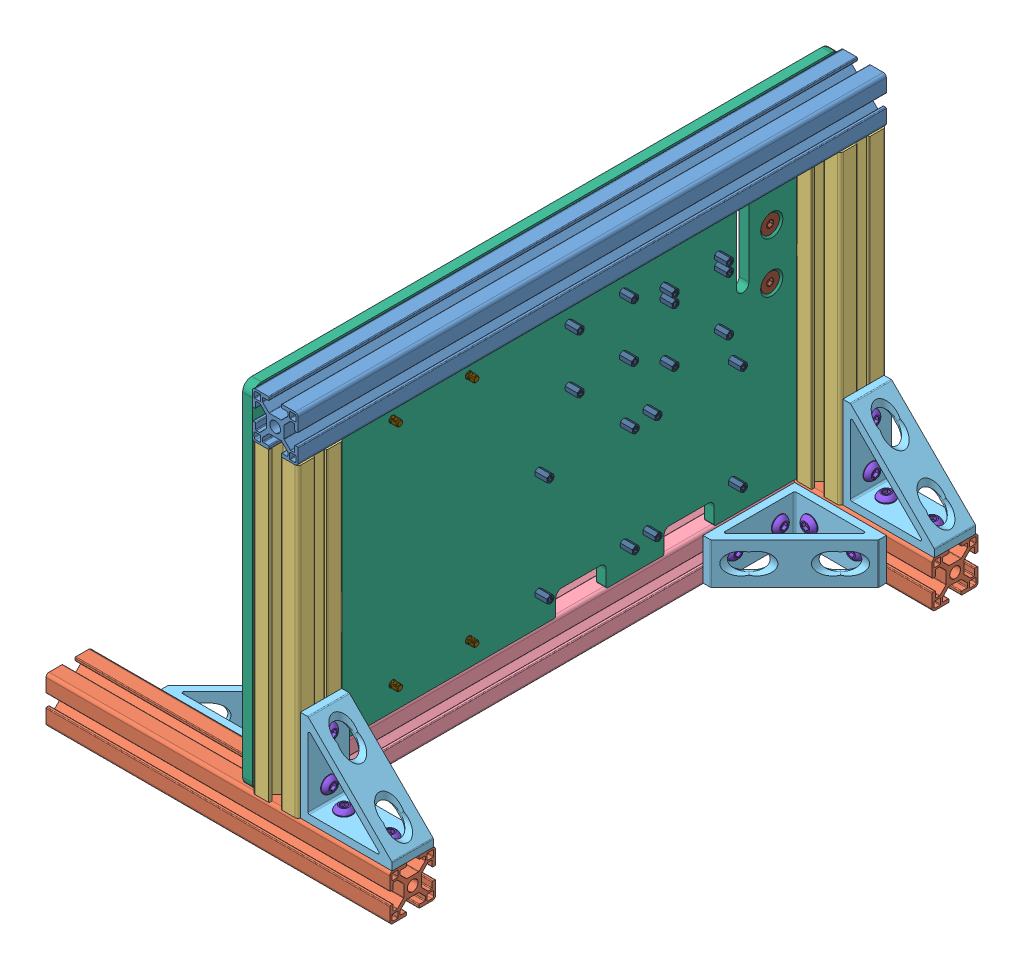
SolidWorks assembly 001 - Machine Frame, configuration Default. Lengths in mm.
Overall size (225 260 385).
71 component instances, 11 part files, 65 mates.
Components (placement in the parent):
- SP - 3030x295mm Extrusion - Phidgets TSL4002_0-1: SP - 3030x295mm Extrusion - Phidgets TSL4002_0 [5537T784] at origin size (30 30 385)
- SP - 3030x225mm Extrusion - Phidgets TSL4002_0-1: SP - 3030x225mm Extrusion - Phidgets TSL4002_0 [5537T784] at (-37.5001 -229.9999 -177.5001) x (0 0 -1) z (1 0 0) size (30 30 225)
- SP - 3030x225mm Extrusion - Phidgets TSL4002_0-2: SP - 3030x225mm Extrusion - Phidgets TSL4002_0 [5537T784] at (-37.5001 -229.9999 177.4998) x (0 0 1) z (-1 0 0) size (30 30 225)
- SP - 3030x200mm Extrusion - Phidgets TSL4002_0-1: SP - 3030x200mm Extrusion - Phidgets TSL4002_0 [5537T784] at (0 -114.9999 177.5001) x (1 0 0) z (0 1 0) size (30 30 200)
- SP - 3030x200mm Extrusion - Phidgets TSL4002_0-2: SP - 3030x200mm Extrusion - Phidgets TSL4002_0 [5537T784] at (0 -114.9999 -177.5001) x (1 0 0) z (0 -1 0) size (30 30 200)
- SP - 3030x265mm Extrusion - Phidgets TSL4002_0-1: SP - 3030x265mm Extrusion - Phidgets TSL4002_0 [5537T784] at (-29.9999 -229.9999 -0.0001) size (30 30 325)
- SP - 3030 Extrusion Bracket - McMaster-Carr 5537T659-1: SP - 3030 Extrusion Bracket - McMaster-Carr 5537T659 [5537T659] at (14.9999 -214.9999 177.5001) size (60 60 27)
- SP - 3030 Extrusion Bracket - McMaster-Carr 5537T659-2: SP - 3030 Extrusion Bracket - McMaster-Carr 5537T659 [5537T659] at (14.9999 -214.9999 -177.5001) size (60 60 27)
- SP - 3030 Extrusion Bracket - McMaster-Carr 5537T659-3: SP - 3030 Extrusion Bracket - McMaster-Carr 5537T659 [5537T659] at (-14.9999 -229.9999 -162.5001) x (1 0 0) z (0 -1 0) size (60 60 27)
- SP - 3030 Extrusion Bracket - McMaster-Carr 5537T659-4: SP - 3030 Extrusion Bracket - McMaster-Carr 5537T659 [5537T659] at (-44.9998 -229.9999 162.4999) x (0 0 -1) z (0 1 0) size (60 60 27)
- 001-102 - Frame Wall-1: 001-102 - Frame Wall [Default] at (-14.9999 -115.0001 0) x (0 0 1) z (0 -1 0) size (385 6.35 230)
- 001-101 - Motor Bracket-1: 001-101 - Motor Bracket [Default] at (-102.0001 -187.4998 -162.5001) x (0 -1 0) z (0 0 1) size (115 96 6.35)
- SP - M6x14 BHCS - McMaster-Carr 91239A319-1: SP - M6x14 BHCS - McMaster-Carr 91239A319 [91239A319] at (23.2999 -169.9999 177.5001) x (0 0.055592 -0.998454) z (1 0 0) size (10.5 10.5 17.89)
- SP - M6x14 BHCS - McMaster-Carr 91239A319-3: SP - M6x14 BHCS - McMaster-Carr 91239A319 [91239A319] at (23.1999 -199.9999 177.5001) x (0 0.055592 -0.998454) z (1 0 0) size (10.5 10.5 17.89)
- SP - M6x14 BHCS - McMaster-Carr 91239A319-6: SP - M6x14 BHCS - McMaster-Carr 91239A319 [91239A319] at (23.1999 -199.9999 -177.5001) x (0 0.055592 -0.998454) z (1 0 0) size (10.5 10.5 17.89)
- SP - M6x14 BHCS - McMaster-Carr 91239A319-7: SP - M6x14 BHCS - McMaster-Carr 91239A319 [91239A319] at (23.1999 -169.9999 -177.5001) x (0 0.055592 -0.998454) z (1 0 0) size (10.5 10.5 17.89)
- SP - M6x14 BHCS - McMaster-Carr 91239A319-8: SP - M6x14 BHCS - McMaster-Carr 91239A319 [91239A319] at (-24.6499 -200.0001 -177.5) x (0 0 1) z (-1 0 0) size (10.5 10.5 17.89)
- SP - M6x14 BHCS - McMaster-Carr 91239A319-10: SP - M6x14 BHCS - McMaster-Carr 91239A319 [91239A319] at (-24.5499 -114.9999 -177.5001) x (0 0 1) z (-1 0 0) size (10.5 10.5 17.89)
- SP - M6x14 BHCS - McMaster-Carr 91239A319-11: SP - M6x14 BHCS - McMaster-Carr 91239A319 [91239A319] at (-24.5499 -30.0001 -177.5) x (0 0 1) z (-1 0 0) size (10.5 10.5 17.89)
- SP - M6x14 BHCS - McMaster-Carr 91239A319-12: SP - M6x14 BHCS - McMaster-Carr 91239A319 [91239A319] at (-24.5499 -0.0001 -172.5) x (0 0 1) z (-1 0 0) size (10.5 10.5 17.89)
- SP - M6x14 BHCS - McMaster-Carr 91239A319-13: SP - M6x14 BHCS - McMaster-Carr 91239A319 [91239A319] at (-24.5499 -0.0001 -57.5) x (0 0 1) z (-1 0 0) size (10.5 10.5 17.89)
- SP - M6x14 BHCS - McMaster-Carr 91239A319-14: SP - M6x14 BHCS - McMaster-Carr 91239A319 [91239A319] at (-24.5499 -0.0001 57.5) x (0 0 1) z (-1 0 0) size (10.5 10.5 17.89)
- SP - M6x14 BHCS - McMaster-Carr 91239A319-15: SP - M6x14 BHCS - McMaster-Carr 91239A319 [91239A319] at (-24.5499 -0.0001 172.5) x (0 0 1) z (-1 0 0) size (10.5 10.5 17.89)
- SP - M6x14 BHCS - McMaster-Carr 91239A319-16: SP - M6x14 BHCS - McMaster-Carr 91239A319 [91239A319] at (-24.5499 -30.0001 177.5) x (0 0 1) z (-1 0 0) size (10.5 10.5 17.89)
- SP - M6x14 BHCS - McMaster-Carr 91239A319-17: SP - M6x14 BHCS - McMaster-Carr 91239A319 [91239A319] at (-24.5499 -115.0001 177.5) x (0 0 1) z (-1 0 0) size (10.5 10.5 17.89)
- SP - M6x14 BHCS - McMaster-Carr 91239A319-18: SP - M6x14 BHCS - McMaster-Carr 91239A319 [91239A319] at (-24.5499 -200.0001 177.5) x (0 0 1) z (-1 0 0) size (10.5 10.5 17.89)
- SP - M6x14 BHCS - McMaster-Carr 91239A319-19: SP - M6x14 BHCS - McMaster-Carr 91239A319 [91239A319] at (-72.0001 -229.9998 -152.8501) size (10.5 10.5 17.89)
- SP - M6x14 BHCS - McMaster-Carr 91239A319-20: SP - M6x14 BHCS - McMaster-Carr 91239A319 [91239A319] at (-102.0001 -229.9998 -152.8501) size (10.5 10.5 17.89)
- SP - M6x14 BHCS - McMaster-Carr 91239A319-21: SP - M6x14 BHCS - McMaster-Carr 91239A319 [91239A319] at (-132.0001 -229.9998 -152.8501) size (10.5 10.5 17.89)
- SP - M4x10 FHCS - McMaster-Carr 91294A190-1: SP - M4x10 FHCS - McMaster-Carr 91294A190 [91294A190] at (-19.9499 -49.0001 50.75) x (0 -0.866025 0.5) z (-1 0 0) size (8 8 10.39)
- SP - M4x10 FHCS - McMaster-Carr 91294A190-2: SP - M4x10 FHCS - McMaster-Carr 91294A190 [91294A190] at (-19.9499 -199.0001 50.75) x (0 -0.866025 0.5) z (-1 0 0) size (8 8 10.39)
- SP - M4x10 FHCS - McMaster-Carr 91294A190-3: SP - M4x10 FHCS - McMaster-Carr 91294A190 [91294A190] at (-19.9499 -49.0001 100.75) x (0 -0.866025 0.5) z (-1 0 0) size (8 8 10.39)
- SP - M4x10 FHCS - McMaster-Carr 91294A190-4: SP - M4x10 FHCS - McMaster-Carr 91294A190 [91294A190] at (-19.9499 -199.0001 100.75) x (0 -0.866025 0.5) z (-1 0 0) size (8 8 10.39)
- SP - M6x14 BHCS - McMaster-Carr 91239A319-22: SP - M6x14 BHCS - McMaster-Carr 91239A319 [91239A319] at (-53.2998 -229.9999 117.4999) x (0 0.031783 0.999495) z (-1 0 0) size (10.5 10.5 17.89)
- SP - M6x14 BHCS - McMaster-Carr 91239A319-23: SP - M6x14 BHCS - McMaster-Carr 91239A319 [91239A319] at (-53.2998 -229.9999 147.4999) x (0 0 1) z (-1 0 0) size (10.5 10.5 17.89)
- SP - M6x14 BHCS - McMaster-Carr 91239A319-24: SP - M6x14 BHCS - McMaster-Carr 91239A319 [91239A319] at (-59.9998 -229.9999 154.1999) x (-0.965185 0.26157 0) z (0 0 -1) size (10.5 10.5 17.89)
- SP - M6x14 BHCS - McMaster-Carr 91239A319-25: SP - M6x14 BHCS - McMaster-Carr 91239A319 [91239A319] at (-89.9998 -229.9999 154.1999) x (-0.968136 0.250427 0) z (0 0 -1) size (10.5 10.5 17.89)
- SP - M6x14 BHCS - McMaster-Carr 91239A319-26: SP - M6x14 BHCS - McMaster-Carr 91239A319 [91239A319] at (30.0001 -229.9999 -154.2001) x (0.986862 0.161565 0) z (0 0 1) size (10.5 10.5 17.89)
- SP - M6x14 BHCS - McMaster-Carr 91239A319-27: SP - M6x14 BHCS - McMaster-Carr 91239A319 [91239A319] at (0.0001 -229.9999 -154.2001) x (0.986862 0.161565 0) z (0 0 1) size (10.5 10.5 17.89)
- SP - M6x14 BHCS - McMaster-Carr 91239A319-28: SP - M6x14 BHCS - McMaster-Carr 91239A319 [91239A319] at (29.9999 -206.6999 -177.5001) x (-0.055592 0 -0.998454) z (0 1 0) size (10.5 10.5 17.89)
- SP - M6x14 BHCS - McMaster-Carr 91239A319-30: SP - M6x14 BHCS - McMaster-Carr 91239A319 [91239A319] at (59.9999 -206.6999 -177.5001) x (-0.055592 0 -0.998454) z (0 1 0) size (10.5 10.5 17.89)
- SP - M6x14 BHCS - McMaster-Carr 91239A319-31: SP - M6x14 BHCS - McMaster-Carr 91239A319 [91239A319] at (29.9999 -206.6999 177.4999) x (-0.055592 0 -0.998454) z (0 1 0) size (10.5 10.5 17.89)
- SP - M6x14 BHCS - McMaster-Carr 91239A319-32: SP - M6x14 BHCS - McMaster-Carr 91239A319 [91239A319] at (59.9999 -206.6999 177.4999) x (-0.055592 0 -0.998454) z (0 1 0) size (10.5 10.5 17.89)
- SP - M3xM3x8 Standoff - McMaster-Carr 98952A106-1: SP - M3xM3x8 Standoff - McMaster-Carr 98952A106 [98952A106] at (-13.3499 -195.0001 -121.313) x (-1 0 0) z (0 -0.866025 -0.5) size (13.03 5.2 4.5)
- SP - M3xM3x8 Standoff - McMaster-Carr 98952A106-2: SP - M3xM3x8 Standoff - McMaster-Carr 98952A106 [98952A106] at (-13.3499 -195.0001 -50.5626) x (-1 0 0) z (0 -0.866025 -0.5) size (13.03 5.2 4.5)
- SP - M3xM3x8 Standoff - McMaster-Carr 98952A106-3: SP - M3xM3x8 Standoff - McMaster-Carr 98952A106 [98952A106] at (-13.3499 -195.0001 -65.433) x (-1 0 0) z (0 -0.866025 -0.5) size (13.03 5.2 4.5)
- SP - M3xM3x8 Standoff - McMaster-Carr 98952A106-4: SP - M3xM3x8 Standoff - McMaster-Carr 98952A106 [98952A106] at (-13.3499 -195.0001 5.3174) x (-1 0 0) z (0 -0.866025 -0.5) size (13.03 5.2 4.5)
- SP - M3xM3x8 Standoff - McMaster-Carr 98952A106-5: SP - M3xM3x8 Standoff - McMaster-Carr 98952A106 [98952A106] at (-13.3499 -126.4201 5.3174) x (-1 0 0) z (0 -0.866025 -0.5) size (13.03 5.2 4.5)
- SP - M3xM3x8 Standoff - McMaster-Carr 98952A106-6: SP - M3xM3x8 Standoff - McMaster-Carr 98952A106 [98952A106] at (-13.3499 -126.4201 -50.5626) x (-1 0 0) z (0 -0.866025 -0.5) size (13.03 5.2 4.5)
- SP - M3xM3x8 Standoff - McMaster-Carr 98952A106-7: SP - M3xM3x8 Standoff - McMaster-Carr 98952A106 [98952A106] at (-13.3499 -126.4201 -65.433) x (-1 0 0) z (0 -0.866025 -0.5) size (13.03 5.2 4.5)
- SP - M3xM3x8 Standoff - McMaster-Carr 98952A106-8: SP - M3xM3x8 Standoff - McMaster-Carr 98952A106 [98952A106] at (-13.3499 -126.4201 -121.313) x (-1 0 0) z (0 -0.866025 -0.5) size (13.03 5.2 4.5)
- SP - M3xM3x8 Standoff - McMaster-Carr 98952A106-9: SP - M3xM3x8 Standoff - McMaster-Carr 98952A106 [98952A106] at (-13.3499 -104.1201 -112.2063) x (-1 0 0) z (0 -0.866025 -0.5) size (13.03 5.2 4.5)
- SP - M3xM3x8 Standoff - McMaster-Carr 98952A106-10: SP - M3xM3x8 Standoff - McMaster-Carr 98952A106 [98952A106] at (-13.3499 -104.1201 -76.6463) x (-1 0 0) z (0 -0.866025 -0.5) size (13.03 5.2 4.5)
- SP - M3xM3x8 Standoff - McMaster-Carr 98952A106-11: SP - M3xM3x8 Standoff - McMaster-Carr 98952A106 [98952A106] at (-13.3499 -88.0249 -14.5067) x (-1 0 0) z (0 -0.866025 -0.5) size (13.03 5.2 4.5)
- SP - M3xM3x8 Standoff - McMaster-Carr 98952A106-12: SP - M3xM3x8 Standoff - McMaster-Carr 98952A106 [98952A106] at (-13.3499 -88.0249 -50.0667) x (-1 0 0) z (0 -0.866025 -0.5) size (13.03 5.2 4.5)
- SP - M3xM3x8 Standoff - McMaster-Carr 98952A106-13: SP - M3xM3x8 Standoff - McMaster-Carr 98952A106 [98952A106] at (-13.3499 -68.5601 -112.2063) x (-1 0 0) z (0 -0.866025 -0.5) size (13.03 5.2 4.5)
- SP - M3xM3x8 Standoff - McMaster-Carr 98952A106-14: SP - M3xM3x8 Standoff - McMaster-Carr 98952A106 [98952A106] at (-13.3499 -62.5601 -112.2063) x (-1 0 0) z (0 -0.866025 -0.5) size (13.03 5.2 4.5)
- SP - M3xM3x8 Standoff - McMaster-Carr 98952A106-15: SP - M3xM3x8 Standoff - McMaster-Carr 98952A106 [98952A106] at (-13.3499 -62.5601 -76.6463) x (-1 0 0) z (0 -0.866025 -0.5) size (13.03 5.2 4.5)
- SP - M3xM3x8 Standoff - McMaster-Carr 98952A106-16: SP - M3xM3x8 Standoff - McMaster-Carr 98952A106 [98952A106] at (-13.3499 -68.5601 -76.6463) x (-1 0 0) z (0 -0.866025 -0.5) size (13.03 5.2 4.5)
- SP - M3xM3x8 Standoff - McMaster-Carr 98952A106-17: SP - M3xM3x8 Standoff - McMaster-Carr 98952A106 [98952A106] at (-13.3499 -27.0001 -76.6463) x (-1 0 0) z (0 -0.866025 -0.5) size (13.03 5.2 4.5)
- SP - M3xM3x8 Standoff - McMaster-Carr 98952A106-18: SP - M3xM3x8 Standoff - McMaster-Carr 98952A106 [98952A106] at (-13.3499 -27.0001 -112.2063) x (-1 0 0) z (0 -0.866025 -0.5) size (13.03 5.2 4.5)
- SP - M3xM3x8 Standoff - McMaster-Carr 98952A106-19: SP - M3xM3x8 Standoff - McMaster-Carr 98952A106 [98952A106] at (-13.3499 -52.4649 -50.0667) x (-1 0 0) z (0 -0.866025 -0.5) size (13.03 5.2 4.5)
- SP - M3xM3x8 Standoff - McMaster-Carr 98952A106-20: SP - M3xM3x8 Standoff - McMaster-Carr 98952A106 [98952A106] at (-13.3499 -52.4649 -14.5067) x (-1 0 0) z (0 -0.866025 -0.5) size (13.03 5.2 4.5)
- SP - M6x15 FHCS - McMaster-Carr 92125A111-1: SP - M6x15 FHCS - McMaster-Carr 92125A111 [92125A111] at (-15.9999 -30.0001 147.5) x (0 0 -1) z (1 0 0) size (12 12 15.58)
- SP - M6x15 FHCS - McMaster-Carr 92125A111-2: SP - M6x15 FHCS - McMaster-Carr 92125A111 [92125A111] at (-15.9999 -30.0001 -147.5) x (0 0 -1) z (1 0 0) size (12 12 15.58)
- SP - M6x15 FHCS - McMaster-Carr 92125A111-3: SP - M6x15 FHCS - McMaster-Carr 92125A111 [92125A111] at (-15.9999 -63.0001 147.5) x (0 0 -1) z (1 0 0) size (12 12 15.58)
- SP - M6x15 FHCS - McMaster-Carr 92125A111-4: SP - M6x15 FHCS - McMaster-Carr 92125A111 [92125A111] at (-15.9999 -63.0001 -147.5) x (0 0 -1) z (1 0 0) size (12 12 15.58)
- SP - M6x15 FHCS - McMaster-Carr 92125A111-5: SP - M6x15 FHCS - McMaster-Carr 92125A111 [92125A111] at (-15.9999 -96.0001 147.5) x (0 0 -1) z (1 0 0) size (12 12 15.58)
- SP - M6x15 FHCS - McMaster-Carr 92125A111-6: SP - M6x15 FHCS - McMaster-Carr 92125A111 [92125A111] at (-15.9999 -96.0001 -147.5) x (0 0 -1) z (1 0 0) size (12 12 15.58)
- SP - M6x14 BHCS - McMaster-Carr 91239A319-33: SP - M6x14 BHCS - McMaster-Carr 91239A319 [91239A319] at (-6.6999 -229.9999 -117.5001) x (0 0.055592 -0.998454) z (1 0 0) size (10.5 10.5 17.89)
- SP - M6x14 BHCS - McMaster-Carr 91239A319-34: SP - M6x14 BHCS - McMaster-Carr 91239A319 [91239A319] at (-6.6999 -229.9999 -147.5001) x (0 0.055592 -0.998454) z (1 0 0) size (10.5 10.5 17.89)
Mates (geometry in assembly coordinates):
- Coincident1: coincident anti-aligned: plane of SP - 3030x295mm Extrusion - Phidgets TSL4002_0-1 through (4.5 -14.9999 192.5) normal (0 -1 0); plane of SP - 3030x200mm Extrusion - Phidgets TSL4002_0-1 through (14.4999 -14.9999 182.0001) normal (0 1 0)
- Coincident2: coincident aligned: plane of SP - 3030x295mm Extrusion - Phidgets TSL4002_0-1 through (14.4999 -4.5 192.5) normal (0 0 1); plane of SP - 3030x200mm Extrusion - Phidgets TSL4002_0-1 through (4.5 -14.9999 192.5) normal (0 0 1)
- Coincident3: coincident aligned: plane of SP - 3030x295mm Extrusion - Phidgets TSL4002_0-1 through (14.9999 -12.9999 192.5) normal (1 0 0); plane of SP - 3030x200mm Extrusion - Phidgets TSL4002_0-1 through (14.9999 -14.9999 190.5) normal (1 0 0)
- Coincident4: coincident anti-aligned: plane of SP - 3030x295mm Extrusion - Phidgets TSL4002_0-1 through (4.5 -14.9999 192.5) normal (0 -1 0); plane of SP - 3030x200mm Extrusion - Phidgets TSL4002_0-2 through (14.4999 -14.9999 -182.0001) normal (0 1 0)
- Coincident5: coincident aligned: plane of SP - 3030x295mm Extrusion - Phidgets TSL4002_0-1 through (14.4999 -4.5 -192.5) normal (0 0 -1); plane of SP - 3030x200mm Extrusion - Phidgets TSL4002_0-2 through (-12.9999 -214.9999 -192.5) normal (0 0 -1)
- Coincident6: coincident aligned: plane of SP - 3030x295mm Extrusion - Phidgets TSL4002_0-1 through (14.9999 -12.9999 192.5) normal (1 0 0); plane of SP - 3030x200mm Extrusion - Phidgets TSL4002_0-2 through (14.9999 -214.9999 -190.5) normal (1 0 0)
- Coincident8: coincident anti-aligned: plane of SP - 3030x200mm Extrusion - Phidgets TSL4002_0-2 through (-4.5 -214.9999 -162.5001) normal (0 0 1); plane of SP - 3030x265mm Extrusion - Phidgets TSL4002_0-1 through (-15.4999 -234.4999 -162.5001) normal (0 0 -1)
- Coincident9: coincident anti-aligned: plane of SP - 3030x200mm Extrusion - Phidgets TSL4002_0-2 through (14.4999 -214.9999 -182.0001) normal (0 -1 0); plane of SP - 3030x265mm Extrusion - Phidgets TSL4002_0-1 through (-34.4999 -214.9999 162.4999) normal (0 1 0)
- Coincident10: coincident aligned: plane of SP - 3030x225mm Extrusion - Phidgets TSL4002_0-1 through (74.9999 -225.4999 -192.5) normal (0 0 -1); plane of SP - 3030x200mm Extrusion - Phidgets TSL4002_0-2 through (-12.9999 -214.9999 -192.5) normal (0 0 -1)
- Coincident11: coincident anti-aligned: plane of SP - 3030x225mm Extrusion - Phidgets TSL4002_0-1 through (74.9999 -214.9999 -190.5) normal (0 1 0); plane of SP - 3030x200mm Extrusion - Phidgets TSL4002_0-2 through (14.4999 -214.9999 -182.0001) normal (0 -1 0)
- Coincident12: coincident anti-aligned: plane of SP - 3030x225mm Extrusion - Phidgets TSL4002_0-2 through (-150.0001 -234.4999 162.4999) normal (0 0 -1); plane of SP - 3030x265mm Extrusion - Phidgets TSL4002_0-1 through (-15.4999 -234.4999 162.4999) normal (0 0 1)
- Coincident13: coincident anti-aligned: plane of SP - 3030x225mm Extrusion - Phidgets TSL4002_0-2 through (-150.0001 -214.9999 172.9998) normal (0 1 0); plane of SP - 3030x200mm Extrusion - Phidgets TSL4002_0-1 through (14.4999 -214.9999 182.0001) normal (0 -1 0)
- Coincident14: coincident aligned: plane of SP - 3030x225mm Extrusion - Phidgets TSL4002_0-1 through (74.9999 -234.4999 -192) normal (1 0 0); plane of SP - 3030x225mm Extrusion - Phidgets TSL4002_0-2 through (74.9999 -234.4999 191.9998) normal (1 0 0)
- Distance1: distance = 60 mm aligned: plane of SP - 3030x225mm Extrusion - Phidgets TSL4002_0-1 through (74.9999 -234.4999 -192) normal (1 0 0); plane of SP - 3030x200mm Extrusion - Phidgets TSL4002_0-2 through (14.9999 -214.9999 -190.5) normal (1 0 0)
- Coincident16: coincident anti-aligned: plane of SP - 3030x225mm Extrusion - Phidgets TSL4002_0-1 through (74.9999 -214.9999 -173.0001) normal (0 1 0); plane of SP - 3030 Extrusion Bracket - McMaster-Carr 5537T659-1 through (14.9999 -214.9999 164.0001) normal (0 -1 0)
- Coincident17: coincident anti-aligned: plane of SP - 3030x200mm Extrusion - Phidgets TSL4002_0-2 through (14.9999 -214.9999 -173.0001) normal (1 0 0); plane of SP - 3030 Extrusion Bracket - McMaster-Carr 5537T659-1 through (14.9999 -214.9999 164.0001) normal (-1 0 0)
- Coincident19: coincident anti-aligned: plane of SP - 3030x225mm Extrusion - Phidgets TSL4002_0-1 through (74.9999 -214.9999 -190.5) normal (0 1 0); plane of SP - 3030 Extrusion Bracket - McMaster-Carr 5537T659-2 through (14.9999 -214.9999 -191.0001) normal (0 -1 0)
- Coincident20: coincident anti-aligned: plane of SP - 3030x200mm Extrusion - Phidgets TSL4002_0-2 through (14.9999 -214.9999 -190.5) normal (1 0 0); plane of SP - 3030 Extrusion Bracket - McMaster-Carr 5537T659-2 through (14.9999 -214.9999 -191.0001) normal (-1 0 0)
- Coincident22: coincident anti-aligned: plane of SP - 3030x225mm Extrusion - Phidgets TSL4002_0-1 through (74.9999 -216.9999 -162.5001) normal (0 0 1); plane of SP - 3030 Extrusion Bracket - McMaster-Carr 5537T659-3 through (-14.9999 -216.4999 -162.5001) normal (0 0 -1)
- Coincident23: coincident anti-aligned: plane of SP - 3030x265mm Extrusion - Phidgets TSL4002_0-1 through (-14.9999 -242.9998 162.4999) normal (1 0 0); plane of SP - 3030 Extrusion Bracket - McMaster-Carr 5537T659-3 through (-14.9999 -216.4999 -162.5001) normal (-1 0 0)
- Width2: width aligned: plane of SP - 3030 Extrusion Bracket - McMaster-Carr 5537T659-3 through (-14.9999 -243.4999 -162.5001) normal (0 -1 0); plane of SP - 3030 Extrusion Bracket - McMaster-Carr 5537T659-3 through (-14.9999 -216.4999 -162.5001) normal (0 1 0); plane of SP - 3030x265mm Extrusion - Phidgets TSL4002_0-1 through (-25.4999 -244.9998 162.4999) normal (0 -1 0); plane of SP - 3030x265mm Extrusion - Phidgets TSL4002_0-1 through (-16.9999 -214.9999 162.4999) normal (0 1 0)
- Coincident24: coincident anti-aligned: plane of SP - 3030x225mm Extrusion - Phidgets TSL4002_0-2 through (-150.0001 -216.9999 162.4999) normal (0 0 -1); plane of SP - 3030 Extrusion Bracket - McMaster-Carr 5537T659-4 through (-44.9998 -243.4999 162.4999) normal (0 0 1)
- Coincident25: coincident anti-aligned: plane of SP - 3030x265mm Extrusion - Phidgets TSL4002_0-1 through (-44.9998 -216.9999 162.4999) normal (-1 0 0); plane of SP - 3030 Extrusion Bracket - McMaster-Carr 5537T659-4 through (-44.9998 -243.4999 162.4999) normal (1 0 0)
- Width3: width aligned: plane of SP - 3030 Extrusion Bracket - McMaster-Carr 5537T659-4 through (-44.9998 -243.4999 162.4999) normal (0 -1 0); plane of SP - 3030 Extrusion Bracket - McMaster-Carr 5537T659-4 through (-44.9998 -216.4999 162.4999) normal (0 1 0); plane of SP - 3030x265mm Extrusion - Phidgets TSL4002_0-1 through (-42.9998 -244.9998 162.4999) normal (0 -1 0); plane of SP - 3030x265mm Extrusion - Phidgets TSL4002_0-1 through (-34.4999 -214.9999 162.4999) normal (0 1 0)
- Width4: width aligned: plane of SP - 3030 Extrusion Bracket - McMaster-Carr 5537T659-2 through (14.9999 -214.9999 -164.0001) normal (0 0 1); plane of SP - 3030 Extrusion Bracket - McMaster-Carr 5537T659-2 through (14.9999 -214.9999 -191.0001) normal (0 0 -1); plane of SP - 3030x200mm Extrusion - Phidgets TSL4002_0-2 through (12.9999 -214.9999 -162.5001) normal (0 0 1); plane of SP - 3030x200mm Extrusion - Phidgets TSL4002_0-2 through (4.5 -214.9999 -192.5) normal (0 0 -1)
- Width5: width aligned: plane of SP - 3030 Extrusion Bracket - McMaster-Carr 5537T659-1 through (14.9999 -214.9999 191.0001) normal (0 0 1); plane of SP - 3030 Extrusion Bracket - McMaster-Carr 5537T659-1 through (14.9999 -214.9999 164.0001) normal (0 0 -1); plane of SP - 3030x200mm Extrusion - Phidgets TSL4002_0-1 through (4.5 -14.9999 192.5) normal (0 0 1); plane of SP - 3030x200mm Extrusion - Phidgets TSL4002_0-1 through (12.9999 -14.9999 162.5001) normal (0 0 -1)
- Coincident26: coincident anti-aligned: plane of SP - 3030x295mm Extrusion - Phidgets TSL4002_0-1 through (-14.9999 -4.5 192.5) normal (-1 0 0); plane of 001-102 - Frame Wall-1 through (-14.9999 -115.0001 0) normal (1 0 0)
- Width6: width aligned: plane of 001-102 - Frame Wall-1 through (-21.3499 -215.0001 192.5) normal (0 0 1); plane of 001-102 - Frame Wall-1 through (-21.3499 -215.0001 -192.5) normal (0 0 -1); plane of SP - 3030x200mm Extrusion - Phidgets TSL4002_0-1 through (-12.9999 -14.9999 192.5) normal (0 0 1); plane of SP - 3030x200mm Extrusion - Phidgets TSL4002_0-2 through (-12.9999 -214.9999 -192.5) normal (0 0 -1)
- Coincident27: coincident aligned: plane of SP - 3030x295mm Extrusion - Phidgets TSL4002_0-1 through (-4.5 14.9999 192.5) normal (0 1 0); plane of 001-102 - Frame Wall-1 through (-14.9999 14.9999 0) normal (0 1 0)
- Coincident28: coincident anti-aligned: plane of SP - 3030x225mm Extrusion - Phidgets TSL4002_0-1 through (74.9999 -216.9999 -162.5001) normal (0 0 1); plane of 001-101 - Motor Bracket-1 through (-102.0001 -187.4998 -162.5001) normal (0 0 -1)
- Coincident29: coincident aligned: plane of SP - 3030x225mm Extrusion - Phidgets TSL4002_0-1 through (74.9999 -244.9998 -164.5001) normal (0 -1 0); plane of 001-101 - Motor Bracket-1 through (-150.0001 -244.9998 -156.1501) normal (0 -1 0)
- Coincident30: coincident aligned: plane of SP - 3030x225mm Extrusion - Phidgets TSL4002_0-1 through (-150.0001 -234.4999 -192) normal (-1 0 0); plane of 001-101 - Motor Bracket-1 through (-150.0001 -129.9998 -156.1501) normal (-1 0 0)
- Concentric1: concentric anti-aligned: cylinder of SP - 3030 Extrusion Bracket - McMaster-Carr 5537T659-1 through (28.4999 -169.9999 177.5001) axis (-1 0 0) radius 3.5; cylinder of SP - M6x14 BHCS - McMaster-Carr 91239A319-1 through (23.2999 -169.9999 177.5001) axis (1 0 0) radius 5.25
- Coincident31: coincident anti-aligned: plane of SP - 3030 Extrusion Bracket - McMaster-Carr 5537T659-1 through (19.9999 -209.9999 164.0001) normal (1 0 0); plane of SP - M6x14 BHCS - McMaster-Carr 91239A319-1 through (19.9999 -175.2418 177.2082) normal (-1 0 0)
- Concentric2: concentric aligned: cylinder of 001-102 - Frame Wall-1 through (-21.3499 -200.0001 -177.5) axis (-1 0 0) radius 3.3; cylinder of SP - M6x14 BHCS - McMaster-Carr 91239A319-8 through (-24.6499 -200.0001 -177.5) axis (-1 0 0) radius 5.25
- Coincident32: coincident anti-aligned: plane of 001-102 - Frame Wall-1 through (-21.3499 -115.0001 0) normal (-1 0 0); plane of SP - M6x14 BHCS - McMaster-Carr 91239A319-8 through (-21.3499 -205.2501 -177.5) normal (1 0 0)
- Parallel1: parallel aligned: plane of SP - 3030x200mm Extrusion - Phidgets TSL4002_0-2 through (-12.9999 -214.9999 -192.5) normal (0 0 -1); plane of SP - M6x14 BHCS - McMaster-Carr 91239A319-8 through (-22.3399 -201.1548 -175.5) normal (0 0 -1)
- Coincident34: coincident anti-aligned: plane of 001-101 - Motor Bracket-1 through (-102.0001 -187.4998 -156.1501) normal (0 0 1); plane of SP - M6x14 BHCS - McMaster-Carr 91239A319-19 through (-72.0001 -235.2498 -156.1501) normal (0 0 -1)
- Concentric3: concentric aligned: cylinder of 001-101 - Motor Bracket-1 through (-72.0001 -229.9998 -156.1501) axis (0 0 1) radius 3.3; cylinder of SP - M6x14 BHCS - McMaster-Carr 91239A319-19 through (-72.0001 -229.9998 -152.8501) axis (0 0 1) radius 5.25
- Coincident35: coincident aligned: cone of 001-102 - Frame Wall-1 through (-21.3499 -49.0001 50.75) axis (1 0 0); cone of SP - M4x10 FHCS - McMaster-Carr 91294A190-1 through (-17.6499 -49.0001 50.75) axis (1 0 0)
- Coincident36: coincident anti-aligned: plane of SP - 3030 Extrusion Bracket - McMaster-Carr 5537T659-4 through (-49.9998 -243.4999 157.4999) normal (-1 0 0); plane of SP - M6x14 BHCS - McMaster-Carr 91239A319-23 through (-49.9998 -235.2499 147.4999) normal (1 0 0)
- Concentric4: concentric anti-aligned: cylinder of SP - 3030 Extrusion Bracket - McMaster-Carr 5537T659-4 through (-58.4998 -229.9999 147.4999) axis (1 0 0) radius 3.5; cylinder of SP - M6x14 BHCS - McMaster-Carr 91239A319-23 through (-53.2998 -229.9999 147.4999) axis (-1 0 0) radius 5.25
- Concentric9: concentric anti-aligned: cylinder of SP - 3030 Extrusion Bracket - McMaster-Carr 5537T659-4 through (-58.4998 -229.9999 117.4999) axis (1 0 0) radius 3.5; cylinder of SP - M6x14 BHCS - McMaster-Carr 91239A319-22 through (-53.2998 -229.9999 117.4999) axis (-1 0 0) radius 5.25
- Coincident37: coincident anti-aligned: plane of SP - 3030 Extrusion Bracket - McMaster-Carr 5537T659-4 through (-49.9998 -243.4999 157.4999) normal (-1 0 0); plane of SP - M6x14 BHCS - McMaster-Carr 91239A319-22 through (-49.9998 -235.2472 117.6667) normal (1 0 0)
- Coincident38: coincident anti-aligned: plane of SP - 3030 Extrusion Bracket - McMaster-Carr 5537T659-4 through (-49.9998 -243.4999 157.4999) normal (0 0 -1); plane of SP - M6x14 BHCS - McMaster-Carr 91239A319-25 through (-91.3146 -235.0826 157.4999) normal (0 0 1)
- Concentric10: concentric anti-aligned: cylinder of SP - 3030 Extrusion Bracket - McMaster-Carr 5537T659-4 through (-89.9998 -229.9999 148.9999) axis (0 0 1) radius 3.5; cylinder of SP - M6x14 BHCS - McMaster-Carr 91239A319-25 through (-89.9998 -229.9999 154.1999) axis (0 0 -1) radius 5.25
- Coincident39: coincident anti-aligned: plane of SP - 3030 Extrusion Bracket - McMaster-Carr 5537T659-4 through (-49.9998 -243.4999 157.4999) normal (0 0 -1); plane of SP - M6x14 BHCS - McMaster-Carr 91239A319-24 through (-61.3731 -235.0671 157.4999) normal (0 0 1)
- Concentric11: concentric anti-aligned: cylinder of SP - 3030 Extrusion Bracket - McMaster-Carr 5537T659-4 through (-59.9998 -229.9999 148.9999) axis (0 0 1) radius 3.5; cylinder of SP - M6x14 BHCS - McMaster-Carr 91239A319-24 through (-59.9998 -229.9999 154.1999) axis (0 0 -1) radius 5.25
- Coincident40: coincident anti-aligned: plane of SP - 3030 Extrusion Bracket - McMaster-Carr 5537T659-3 through (-9.9999 -216.4999 -157.5001) normal (0 0 1); plane of SP - M6x14 BHCS - McMaster-Carr 91239A319-26 through (30.8483 -235.1809 -157.5001) normal (0 0 -1)
- Coincident41: coincident anti-aligned: plane of SP - 3030 Extrusion Bracket - McMaster-Carr 5537T659-3 through (-9.9999 -216.4999 -157.5001) normal (0 0 1); plane of SP - M6x14 BHCS - McMaster-Carr 91239A319-27 through (0.8483 -235.1809 -157.5001) normal (0 0 -1)
- Concentric12: concentric anti-aligned: cylinder of SP - 3030 Extrusion Bracket - McMaster-Carr 5537T659-3 through (30.0001 -229.9999 -149.0001) axis (0 0 -1) radius 3.5; cylinder of SP - M6x14 BHCS - McMaster-Carr 91239A319-26 through (30.0001 -229.9999 -154.2001) axis (0 0 1) radius 5.25
- Concentric13: concentric anti-aligned: cylinder of SP - 3030 Extrusion Bracket - McMaster-Carr 5537T659-3 through (0.0001 -229.9999 -149.0001) axis (0 0 -1) radius 3.5; cylinder of SP - M6x14 BHCS - McMaster-Carr 91239A319-27 through (0.0001 -229.9999 -154.2001) axis (0 0 1) radius 5.25
- Coincident42: coincident anti-aligned: plane of SP - 3030 Extrusion Bracket - McMaster-Carr 5537T659-2 through (19.9999 -209.9999 -191.0001) normal (0 1 0); plane of SP - M6x14 BHCS - McMaster-Carr 91239A319-28 through (35.2418 -209.9999 -177.7919) normal (0 -1 0)
- Concentric14: concentric anti-aligned: cylinder of SP - 3030 Extrusion Bracket - McMaster-Carr 5537T659-2 through (29.9999 -201.4999 -177.5001) axis (0 -1 0) radius 3.5; cylinder of SP - M6x14 BHCS - McMaster-Carr 91239A319-28 through (29.9999 -206.6999 -177.5001) axis (0 1 0) radius 5.25
- Coincident44: coincident anti-aligned: plane of 001-102 - Frame Wall-1 through (-14.9999 -115.0001 0) normal (1 0 0); plane of SP - M3xM3x8 Standoff - McMaster-Carr 98952A106-1 through (-14.9999 -193.701 -123.563) normal (-1 0 0)
- Concentric16: concentric aligned: cylinder of 001-102 - Frame Wall-1 through (-14.9999 -195.0001 -121.313) axis (1 0 0) radius 1.25; cylinder of SP - M3xM3x8 Standoff - McMaster-Carr 98952A106-1 through (-13.3499 -195.0001 -121.313) axis (1 0 0) radius 1.1727
- Parallel4: parallel aligned: plane of SP - 3030x200mm Extrusion - Phidgets TSL4002_0-2 through (12.9999 -214.9999 -162.5001) normal (0 0 1); plane of SP - M3xM3x8 Standoff - McMaster-Carr 98952A106-1 through (-6.9999 -196.2991 -119.063) normal (0 0 1)
- Coincident47: coincident aligned: cone of 001-102 - Frame Wall-1 through (-14.9999 -30.0001 147.5) axis (-1 0 0); cone of SP - M6x15 FHCS - McMaster-Carr 92125A111-1 through (-19.2999 -30.0001 147.5) axis (-1 0 0)
- Parallel5: parallel aligned: plane of SP - 3030x200mm Extrusion - Phidgets TSL4002_0-1 through (-4.5 -14.9999 162.5001) normal (0 0 -1); plane of SP - M6x15 FHCS - McMaster-Carr 92125A111-1 through (-18.3099 -28.8454 149.5) normal (0 0 -1)
- Parallel6: parallel aligned: plane of SP - 3030x200mm Extrusion - Phidgets TSL4002_0-1 through (-12.9999 -14.9999 192.5) normal (0 0 1); plane of SP - M4x10 FHCS - McMaster-Carr 91294A190-1 through (-18.3399 -48.2784 49.5) normal (0 0 1)
- Coincident48: coincident anti-aligned: plane of SP - 3030x200mm Extrusion - Phidgets TSL4002_0-1 through (-14.9999 -14.9999 164.5001) normal (-1 0 0); plane of SP - 3030x265mm Extrusion - Phidgets TSL4002_0-1 through (-14.9999 -225.4999 162.4999) normal (1 0 0)
- Concentric17: concentric anti-aligned: cylinder of SP - 3030 Extrusion Bracket - McMaster-Carr 5537T659-3 through (-1.4999 -229.9999 -117.5001) axis (-1 0 0) radius 3.5; cylinder of SP - M6x14 BHCS - McMaster-Carr 91239A319-33 through (-6.6999 -229.9999 -117.5001) axis (1 0 0) radius 5.25
- Concentric18: concentric anti-aligned: cylinder of SP - 3030 Extrusion Bracket - McMaster-Carr 5537T659-3 through (-1.4999 -229.9999 -147.5001) axis (-1 0 0) radius 3.5; cylinder of SP - M6x14 BHCS - McMaster-Carr 91239A319-34 through (-6.6999 -229.9999 -147.5001) axis (1 0 0) radius 5.25
- Coincident49: coincident anti-aligned: plane of SP - 3030 Extrusion Bracket - McMaster-Carr 5537T659-3 through (-9.9999 -216.4999 -157.5001) normal (1 0 0); plane of SP - M6x14 BHCS - McMaster-Carr 91239A319-33 through (-9.9999 -235.2418 -117.792) normal (-1 0 0)
- Coincident50: coincident anti-aligned: plane of SP - 3030 Extrusion Bracket - McMaster-Carr 5537T659-3 through (-9.9999 -216.4999 -157.5001) normal (1 0 0); plane of SP - M6x14 BHCS - McMaster-Carr 91239A319-34 through (-9.9999 -235.2418 -147.792) normal (-1 0 0)
